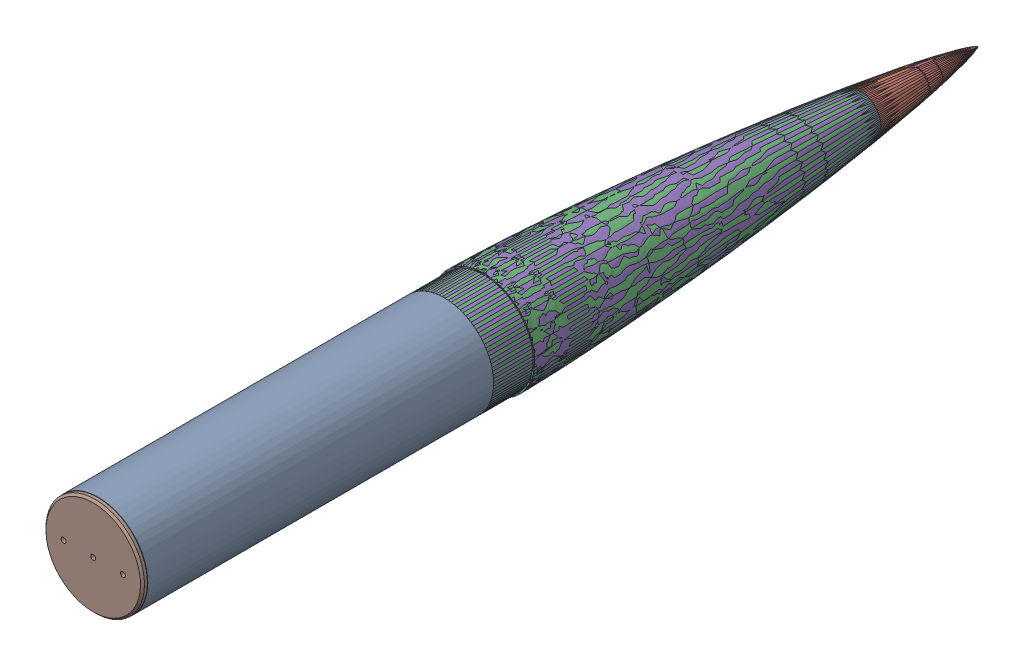
SolidWorks assembly nosecone, configuration Default. Lengths in mm.
Overall size (130.81 130.81 1136.65).
6 component instances, 6 part files, 8 mates.
Components (placement in the parent):
- payload_coupler-1: payload_coupler [Default] at (-134.4098 -50.1685 -159.6507) size (127 127 482.6)
- nosecone_main-1: nosecone_main [Default] at (-35.8351 -36.2675 -845.4507) x (0 0 1) z (-1 0 0) size (688.15 130.81 130.81)
- nosecone_tip-1: nosecone_tip [Default] at (-35.8351 -36.2675 -845.4507) x (0 0 1) z (-0.923728 -0.383049 0) size (685.8 130.81 130.81)
- Eyebolt-1: Eyebolt [3014T45] at (-35.8351 -36.2675 -618.4382) x (-0.923728 -0.383049 0) z (-0.383049 0.923728 0) size (30.16 64.79 14.29)
- payload_coupler_lid-1: payload_coupler_lid [Default] at (-35.8351 -36.2675 -196.4807) x (1 0 0) z (0 1 0) size (113.03 15.88 113.03)
- payload_coupler_bulkhead-1: payload_coupler_bulkhead [Default] at (-35.8351 -36.2675 291.1993) x (1 0 0) z (0 1 0) size (126.49 12.7 126.49)
Mates (geometry in assembly coordinates):
- Coincident1: coincident anti-aligned: circle of payload_coupler-1; circle of nosecone_main-1
- Coincident2: coincident aligned: circle of nosecone_main-1; circle of nosecone_tip-1
- Concentric1: concentric aligned: circle of nosecone_tip-1; circle of Eyebolt-1
- Coincident3: coincident anti-aligned: plane of nosecone_tip-1 through (-35.8351 -36.2675 -642.2507) normal (0 0 1); plane of Eyebolt-1 through (-35.8351 -36.2675 -642.2507) normal (0 0 -1)
- Concentric2: concentric anti-aligned: circle of payload_coupler-1; circle of payload_coupler_lid-1
- Coincident4: coincident aligned: plane of payload_coupler-1 through (-35.8351 -36.2675 -197.7507) normal (0 0 -1); circle of payload_coupler_lid-1
- Coincident5: coincident anti-aligned: plane of payload_coupler-1 through (-35.8351 -36.2675 284.8493) normal (0 0 1); plane of payload_coupler_bulkhead-1 through (-35.8351 -36.2675 284.8493) normal (0 0 -1)
- Concentric3: concentric aligned: circle of payload_coupler-1; circle of payload_coupler_bulkhead-1
